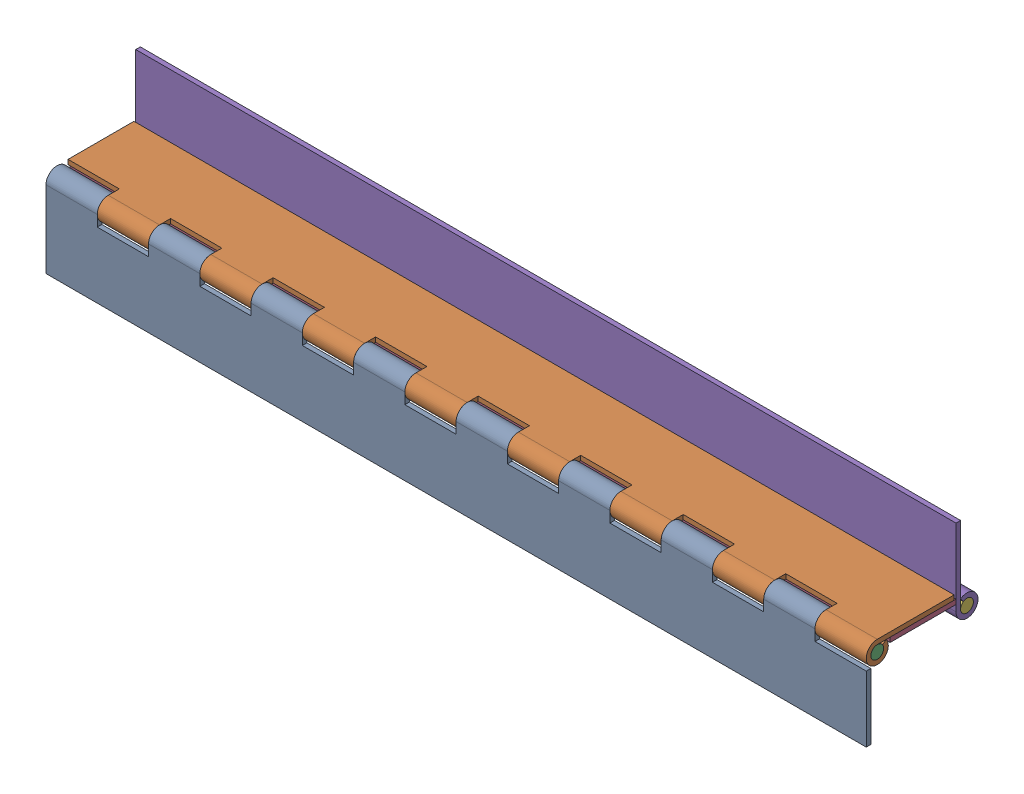
SolidWorks assembly FE-00004-07_ASM, configuration Default. Lengths in mm.
Overall size (406.4 73.91 55.37).
6 component instances, 4 part files, 0 mates.
Components (placement in the parent):
- FE-00004-07-A-1: FE-00004-07-A [Default] at origin size (406.4 43.56 10.92)
- FE-00004-07-A_AF0-1: FE-00004-07-A_AF0 [Default] at (0 5.461 -5.461) x (-1 0 0) z (0 1 0) size (406.4 43.56 10.92)
- FE-00004-07-B-1: FE-00004-07-B [Default] at (0 0 -5.461) size (406.4 6.35 6.35)
- FE-00004-07-A_AF1-1: FE-00004-07-A_AF1 [Default] at (0 3.175 -49.911) x (1 0 0) z (0 1 0) size (406.4 43.56 10.92)
- FE-00004-07-A-2: FE-00004-07-A [Default] at (0 -2.286 -44.45) x (-1 0 0) z (0 0 1) size (406.4 43.56 10.92)
- FE-00004-07-B-2: FE-00004-07-B [Default] at (0 -2.286 -49.911) size (406.4 6.35 6.35)
